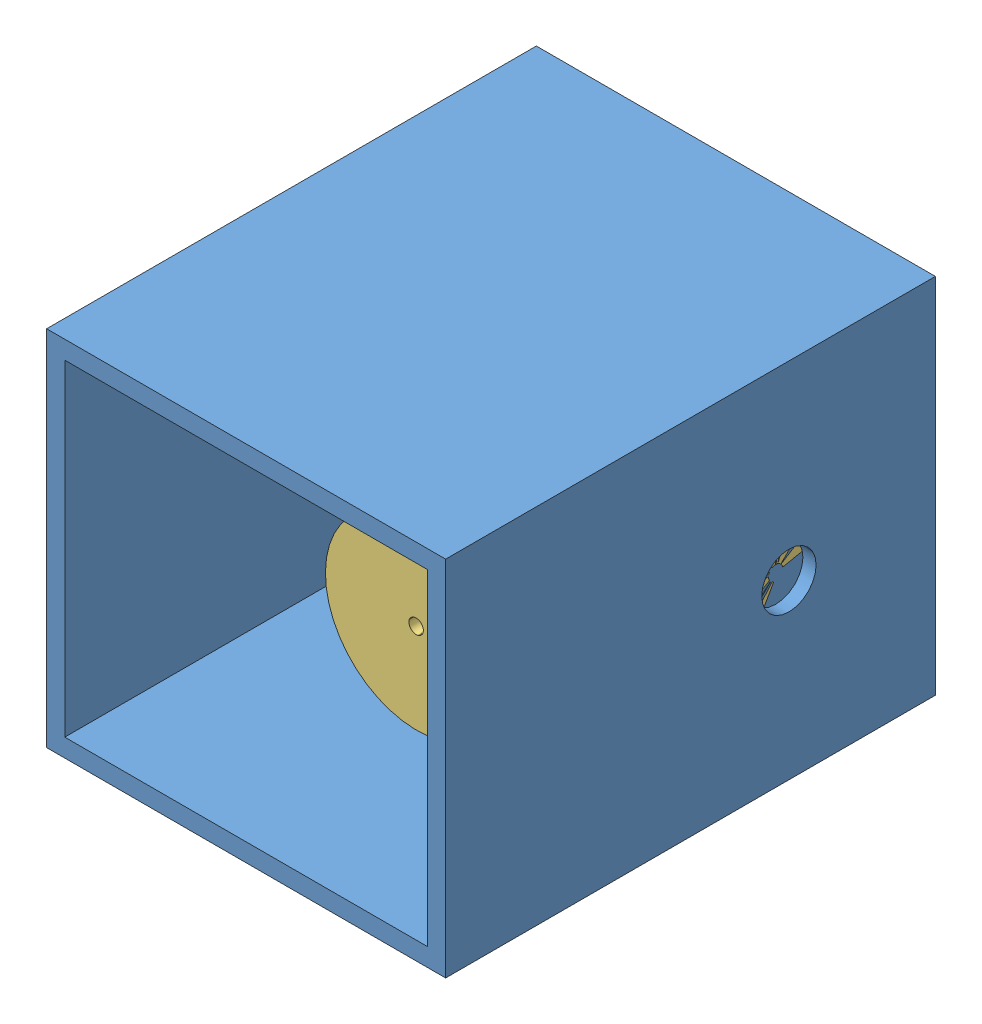
SolidWorks assembly Diffferential motor aries, configuration Default. Lengths in mm.
Overall size (25.45 26.52 31.2).
13 component instances, 3 part files, 0 mates.
Components (placement in the parent):
- Differential box-1: Differential box [Default] at (5.3507 11.3329 9.2636) size (22 20 27)
- Aries project Differential-1: Aries project Differential [Default] at (-7.0512 31.8112 15.5431) x (0.98773 0.030546 -0.153154) z (0.155913 -0.249109 0.955843) size (22.74 20.21 25.25)
  - Differential part 1-3: Differential part 1 [Default] at (6.6336 -19.3941 6.6309) x (0.98773 0.008955 0.155913) z (0.064078 -0.933684 -0.352318) size (10.65 13.87 13.91)
  - Differential part 2-4: Differential part 2 [Default] at (11.5308 -21.8615 6.8199) x (0.98773 0.008955 0.155913) z (-0.120067 0.681953 0.721474) size (9.81 5.94 5.96)
    - straight bevel gear_iso-1: straight bevel gear_iso [ISO - Straight bevel gear 0.3M 19GT 12PT 14.5PA 7FW ---19O3H10MD0.8N] at (-3.5446 0.6303 2.0777) size (9.81 5.94 5.96)
  - Differential part 2-5: Differential part 2 [Default] at (9.6513 -21.0712 6.6203) x (0.142419 0.357986 -0.922802) z (0.893588 0.354464 0.275419) size (9.81 5.94 5.96)
    - straight bevel gear_iso-1: straight bevel gear_iso [ISO - Straight bevel gear 0.3M 19GT 12PT 14.5PA 7FW ---19O3H10MD0.8N] at (-3.5446 0.6303 2.0777) size (9.81 5.94 5.96)
  - Differential part 2-6: Differential part 2 [Default] at (13.2252 -20.4695 8.5856) x (-0.142419 -0.357986 0.922802) z (-0.968764 -0.1408 -0.204134) size (9.81 5.94 5.96)
    - straight bevel gear_iso-1: straight bevel gear_iso [ISO - Straight bevel gear 0.3M 19GT 12PT 14.5PA 7FW ---19O3H10MD0.8N] at (-3.5446 0.6303 2.0777) size (9.81 5.94 5.96)
  - Differential part 2-7: Differential part 2 [Default] at (10.6434 -18.1036 6.6974) x (-0.98773 -0.008955 -0.155913) z (-0.106959 -0.688662 0.71715) size (9.81 5.94 5.96)
    - straight bevel gear_iso-1: straight bevel gear_iso [ISO - Straight bevel gear 0.3M 19GT 12PT 14.5PA 7FW ---19O3H10MD0.8N] at (-3.5446 0.6303 2.0777) size (9.81 5.94 5.96)
  - Differential part 1-4: Differential part 1 [Default] at (12.2662 -18.8312 15.7512) x (0.153433 -0.241744 -0.958133) z (0.933412 -0.282803 0.220828) size (7.08 13.87 13.91)
    - straight bevel gear_iso-4: straight bevel gear_iso [ISO - Straight bevel gear 0.7M 19GT 12PT 14.5PA 1.6FW ---19O10H10MD0.8N] at (0.225 0.7054 0.4074) size (7.08 13.87 13.91)
